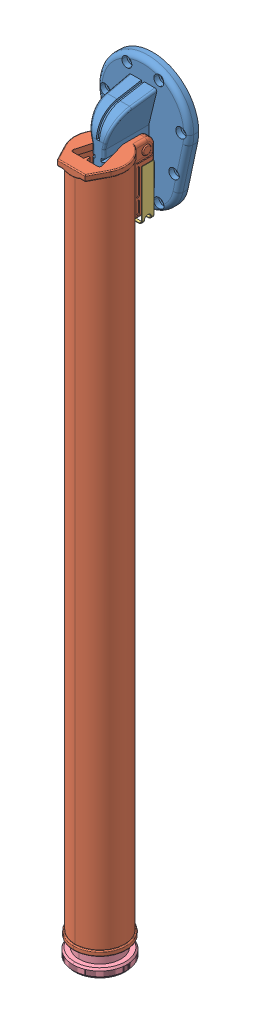
SolidWorks assembly pied de table rabattable Camar replie, configuration Default. Lengths in mm.
Overall size (92 760 81.75).
5 component instances, 4 part files, 0 mates.
Components (placement in the parent):
- pied de table rabattable Camar replie.STEP-1: pied de table rabattable Camar replie.STEP [Default] at origin size (92 760 81.75)
  - base pied_1.STEP-1: base pied_1.STEP [Default] at origin size (92 130 57.2)
  - tube pied_1.STEP-1: tube pied_1.STEP [Default] at (0 -353.5 53) size (53 681 70.75)
  - bouton pied_1.STEP-1: bouton pied_1.STEP [Default] at (0 -84 18.9792) x (-1 0 0) z (0 1 0) size (28 12 50.5)
  - reglage pied_1.STEP-1: reglage pied_1.STEP [Default] at (0 -712 53) size (54.2 50 54.2)
